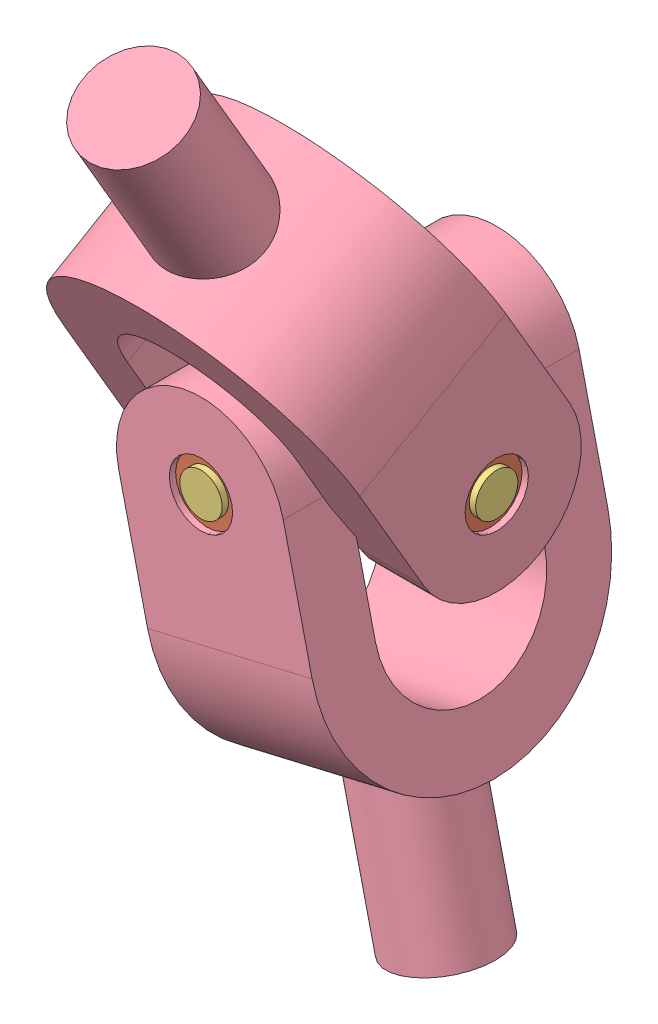
SolidWorks assembly Universal Joint 2003092, configuration Default. Lengths in mm.
Overall size (98.42 254.24 131.1).
11 component instances, 4 part files, 20 mates.
Components (placement in the parent):
- Swivel - 2003091-2: Swivel - 2003091 [Default] at origin size (54.61 25.4 54.61)
- Blushing 2003091-2: Blushing 2003091 [Default] at (0 0 -42.545) size (19.05 19.05 15.24)
- Blushing 2003091-3: Blushing 2003091 [Default] at (-42.545 0 0) x (0 0 -1) z (1 0 0) size (19.05 19.05 15.24)
- Blushing 2003091-4: Blushing 2003091 [Default] at (42.545 0 0) x (0 0 1) z (-1 0 0) size (19.05 19.05 15.24)
- Blushing 2003091-5: Blushing 2003091 [Default] at (0 0 42.545) x (-0.923728 -0.383049 0) z (0 0 -1) size (19.05 19.05 15.24)
- Pin 2003091-1: Pin 2003091 [Default] at (44.45 0 0) x (0 0 1) z (-1 0 0) size (12.7 12.7 34.29)
- Pin 2003091-2: Pin 2003091 [Default] at (0 0 44.45) x (-0.982483 0.186351 0) z (0 0 -1) size (12.7 12.7 34.29)
- Pin 2003091-3: Pin 2003091 [Default] at (0 0 -44.45) x (0.328176 -0.944616 0) z (0 0 1) size (12.7 12.7 34.29)
- Pin 2003091-4: Pin 2003091 [Default] at (-44.45 0 0) x (0 -0.31411 -0.949386) z (1 0 0) size (12.7 12.7 34.29)
- Yoke - 2003091-1: Yoke - 2003091 [Default] at (8.6847 -37.097 0) x (0 0 1) z (0.973674 0.227945 0) size (88.9 153.67 50.8)
- Yoke - 2003091-2: Yoke - 2003091 [Default] at (0 32.8948 19.2235) x (1 0 0) z (0 -0.504554 0.86338) size (88.9 153.67 50.8)
Mates (geometry in assembly coordinates):
- Coincident1: coincident anti-aligned: plane of Blushing 2003091-3 through (-27.305 0 0) normal (1 0 0); plane of Swivel - 2003091-2 through (-27.305 0 0) normal (-1 0 0)
- Coincident3: coincident anti-aligned: plane of Swivel - 2003091-2 through (0 0 27.305) normal (0 0 1); plane of Blushing 2003091-5 through (0 0 27.305) normal (0 0 -1)
- Coincident4: coincident anti-aligned: circle of Swivel - 2003091-2; circle of Blushing 2003091-5
- Coincident5: coincident anti-aligned: plane of Swivel - 2003091-2 through (27.305 0 0) normal (1 0 0); plane of Blushing 2003091-4 through (27.305 0 0) normal (-1 0 0)
- Coincident6: coincident anti-aligned: circle of Swivel - 2003091-2; circle of Blushing 2003091-4
- Coincident7: coincident anti-aligned: plane of Swivel - 2003091-2 through (0 0 -27.305) normal (0 0 -1); plane of Blushing 2003091-2 through (0 0 -27.305) normal (0 0 1)
- Coincident8: coincident aligned: circle of Swivel - 2003091-2; circle of Blushing 2003091-2
- Coincident9: coincident anti-aligned: cylinder of Blushing 2003091-4; cylinder of Pin 2003091-1 through (10.16 0 0) axis (1 0 0) radius 6.35
- Coincident10: coincident anti-aligned: circle of Blushing 2003091-5; cylinder of Pin 2003091-2 through (15.8616 -11.479 19.1621) axis (0 0 1) radius 6.35
- Coincident11: coincident anti-aligned: circle of Blushing 2003091-2; cylinder of Pin 2003091-3 through (0 0 -10.16) axis (0 0 -1) radius 6.35
- Coincident13: coincident aligned: circle of Swivel - 2003091-2; circle of Blushing 2003091-3
- Coincident14: coincident anti-aligned: circle of Blushing 2003091-3; cylinder of Pin 2003091-4 through (-23.276 28.0793 5.4499) axis (-1 0 0) radius 6.35
- Concentric4: concentric anti-aligned: cylinder of Blushing 2003091-3 through (-27.305 0 0) axis (-1 0 0) radius 9.525; cylinder of Yoke - 2003091-2 through (44.45 0 0) axis (1 0 0) radius 9.525
- Concentric6: concentric anti-aligned: cylinder of Blushing 2003091-2 through (0 0 -27.305) axis (0 0 -1) radius 9.525; cylinder of Yoke - 2003091-1 through (0 0 44.45) axis (0 0 1) radius 9.525
- Width1: width aligned: plane of Yoke - 2003091-1 through (33.416 -31.3072 -44.45) normal (0 0 -1); plane of Yoke - 2003091-1 through (33.416 -31.3072 44.45) normal (0 0 1); plane of Blushing 2003091-2 through (0 0 -42.545) normal (0 0 -1); plane of Blushing 2003091-5 through (0 0 42.545) normal (0 0 1)
- Width2: width aligned: plane of Yoke - 2003091-2 through (44.45 20.0791 41.1534) normal (1 0 0); plane of Yoke - 2003091-2 through (-44.45 20.0791 41.1534) normal (-1 0 0); plane of Blushing 2003091-4 through (42.545 0 0) normal (1 0 0); plane of Blushing 2003091-3 through (-42.545 0 0) normal (-1 0 0)
- Coincident24: coincident aligned: plane of Pin 2003091-1 through (44.45 0 0) normal (1 0 0); plane of Yoke - 2003091-2 through (44.45 20.0791 41.1534) normal (1 0 0)
- Coincident25: coincident aligned: plane of Pin 2003091-3 through (0 0 -44.45) normal (0 0 -1); plane of Yoke - 2003091-1 through (33.416 -31.3072 -44.45) normal (0 0 -1)
- Coincident26: coincident aligned: plane of Pin 2003091-4 through (-44.45 0 0) normal (-1 0 0); plane of Yoke - 2003091-2 through (-44.45 20.0791 41.1534) normal (-1 0 0)
- Coincident27: coincident aligned: plane of Pin 2003091-2 through (0 0 44.45) normal (0 0 1); plane of Yoke - 2003091-1 through (33.416 -31.3072 44.45) normal (0 0 1)
